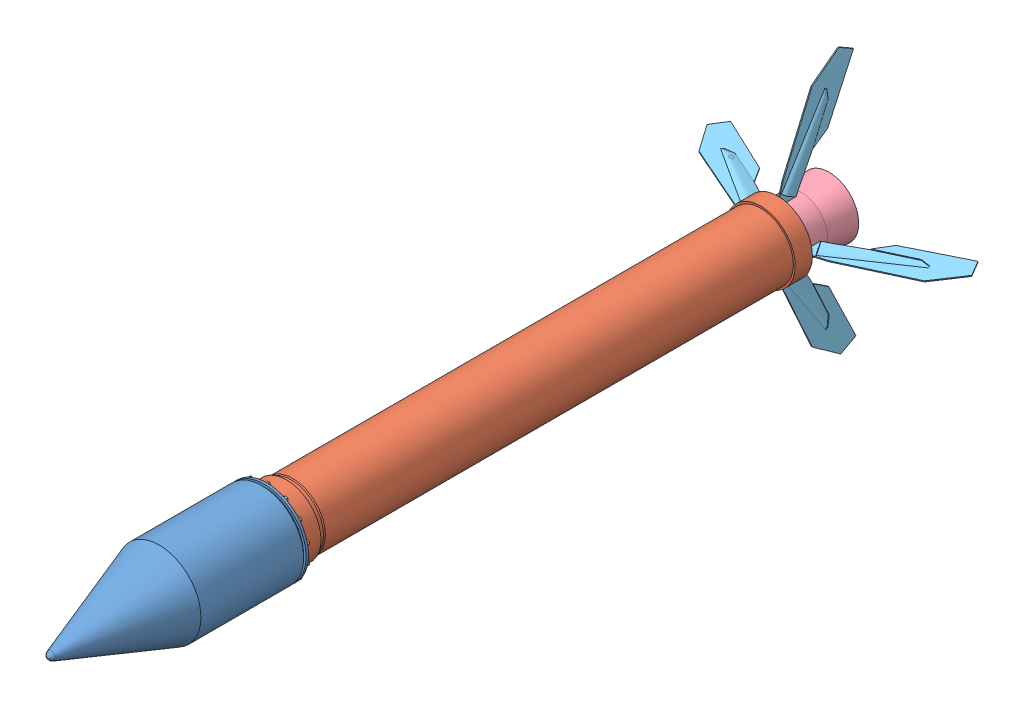
SolidWorks assembly S-25OF, configuration Default. Lengths in mm.
Overall size (1076.03 1076.03 3280.97).
21 component instances, 5 part files, 8 mates.
Components (placement in the parent):
- S-25OF_WH-1: S-25OF_WH [Default] at origin size (340 340 902)
- S-25OF_Motor-1: S-25OF_Motor [Default] at (0.0834 10.0098 -902) x (0.999965 -0.008333 0) z (0 0 1) size (281 281 2068)
- Note-1: Note [Default] at (0 162.5 -900) size (16.17 14 8)
- Note-2: Note [Default] at (-70.5061 146.4074 -900) x (0.900969 0.433884 0) z (0 0 1) size (16.17 14 8)
- Note-3: Note [Default] at (-127.0476 101.3171 -900) x (0.62349 0.781831 0) z (0 0 1) size (16.17 14 8)
- Note-4: Note [Default] at (-158.4258 36.1597 -900) x (0.222521 0.974928 0) z (0 0 1) size (16.17 14 8)
- Note-5: Note [Default] at (-158.4258 -36.1597 -900) x (-0.222521 0.974928 0) z (0 0 1) size (16.17 14 8)
- Note-6: Note [Default] at (-127.0476 -101.3171 -900) x (-0.62349 0.781831 0) z (0 0 1) size (16.17 14 8)
- Note-7: Note [Default] at (-70.5061 -146.4074 -900) x (-0.900969 0.433884 0) z (0 0 1) size (16.17 14 8)
- Note-8: Note [Default] at (0 -162.5 -900) x (-1 0 0) z (0 0 1) size (16.17 14 8)
- Note-9: Note [Default] at (70.5061 -146.4074 -900) x (-0.900969 -0.433884 0) z (0 0 1) size (16.17 14 8)
- Note-10: Note [Default] at (127.0476 -101.3171 -900) x (-0.62349 -0.781831 0) z (0 0 1) size (16.17 14 8)
- Note-11: Note [Default] at (158.4258 -36.1597 -900) x (-0.222521 -0.974928 0) z (0 0 1) size (16.17 14 8)
- Note-12: Note [Default] at (158.4258 36.1597 -900) x (0.222521 -0.974928 0) z (0 0 1) size (16.17 14 8)
- Note-13: Note [Default] at (127.0476 101.3171 -900) x (0.62349 -0.781831 0) z (0 0 1) size (16.17 14 8)
- Note-14: Note [Default] at (70.5061 146.4074 -900) x (0.900969 -0.433884 0) z (0 0 1) size (16.17 14 8)
- S-25OF_Nozzle-1: S-25OF_Nozzle [Default] at (0 0 -2970) size (241.23 241.23 232)
- S-25OF_Stab-1: S-25OF_Stab [Default] at (1.0478 105 -2969.9614) x (0.999657 0 -0.026177) z (0.026177 0 0.999657) size (24.36 436.22 310.62)
- S-25OF_Stab-5: S-25OF_Stab [Default] at (-105 1.0478 -2969.9614) x (0 0.999657 -0.026177) z (0 0.026177 0.999657) size (24.36 436.22 310.62)
- S-25OF_Stab-6: S-25OF_Stab [Default] at (-1.0478 -105 -2969.9614) x (-0.999657 0 -0.026177) z (-0.026177 0 0.999657) size (24.36 436.22 310.62)
- S-25OF_Stab-7: S-25OF_Stab [Default] at (105 -1.0478 -2969.9614) x (0 -0.999657 -0.026177) z (0 -0.026177 0.999657) size (24.36 436.22 310.62)
Mates (geometry in assembly coordinates):
- Coincident1: coordinate: point of S-25OF_WH-1
- Parallel1: parallel aligned: cylinder of S-25OF_WH-1 through (0 0 0) axis (0 0 1) radius 170; cylinder of S-25OF_Motor-1 through (0 0 -902) axis (0 0 1) radius 133
- Concentric3: concentric aligned: cylinder of S-25OF_WH-1 through (0 0 -910) axis (0 0 1) radius 10; cylinder of S-25OF_Motor-1 through (0 0 -912) axis (0 0 1) radius 10
- Coincident2: coincident anti-aligned: plane of S-25OF_WH-1 through (0 155 -902) normal (0 0 -1); plane of S-25OF_Motor-1 through (1.1708 140.4951 -902) normal (0 0 1)
- Coincident3: coincident anti-aligned: cylinder of S-25OF_WH-1 through (0 162.5 -900) axis (0 0 1) radius 2; circle of Note-1
- Coincident4: coincident anti-aligned: plane of S-25OF_WH-1 through (0 170 -892) normal (0 0 -1); plane of Note-1 through (0 162.5 -892) normal (0 0 1)
- Coincident5: coincident anti-aligned: circle of S-25OF_Motor-1; cylinder of S-25OF_Nozzle-1 through (0 0 -2970) axis (0 0 -1) radius 10
- Tangent2: tangent anti-aligned: cylinder of S-25OF_Nozzle-1 through (0 0 -2970) axis (0 0 1) radius 105; plane of S-25OF_Stab-1 through (5.0464 105 -2970.0661) normal (0 -1 0)
